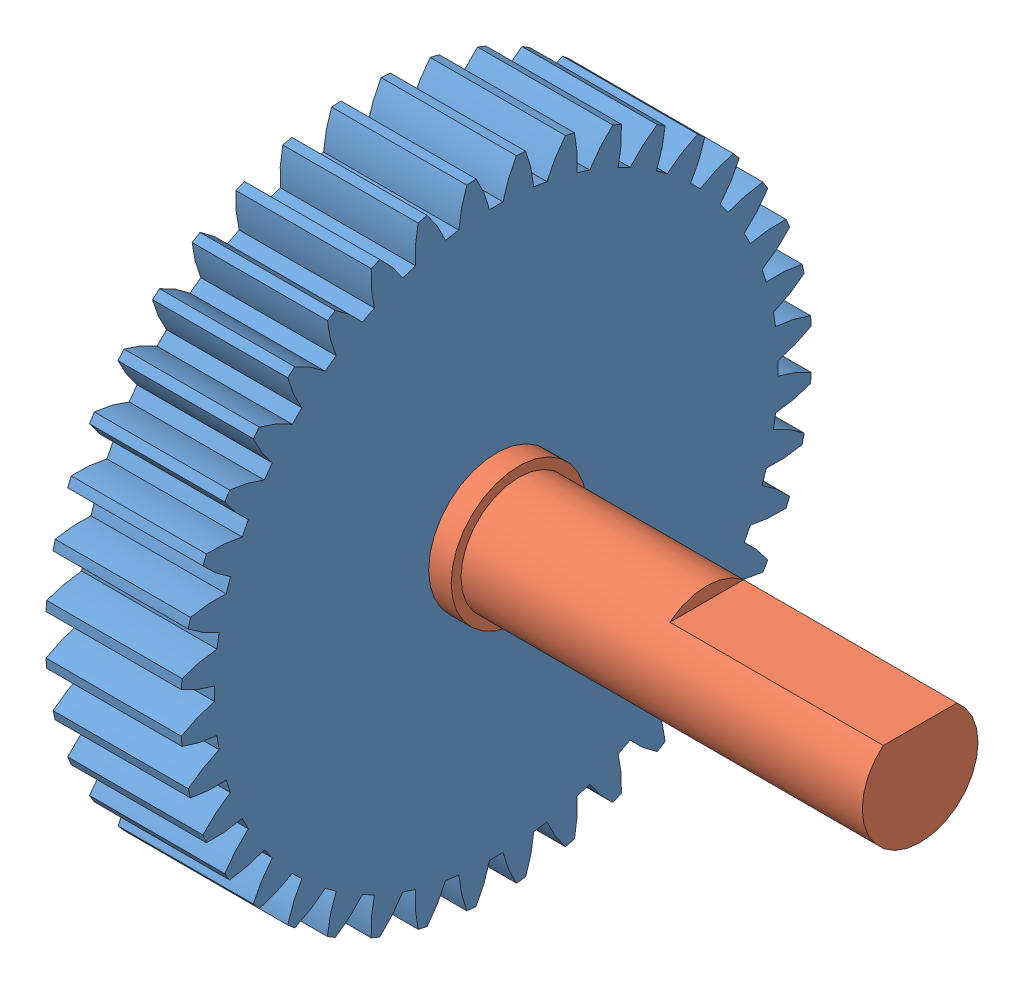
SolidWorks assembly 40_Tooth_Mod1, configuration Default. Lengths in mm.
Overall size (37.2 41.91 41.91).
2 component instances, 2 part files, 2 mates.
Components (placement in the parent):
- Metric - Spur gear 1M 40T 20PA 9FW ---S40N75H50L4N-2: Metric - Spur gear 1M 40T 20PA 9FW ---S40N75H50L4N [Metric - Spur gear 1M 40T 20PA 9FW ---S40N75H50L4N] at (6.894 -1.4709 -4.9997) size (9 41.91 41.91)
- Gear_Shaft-1: Gear_Shaft [Default] at (15.894 -1.4709 -4.9997) size (37.2 9 9)
Mates (geometry in assembly coordinates):
- Concentric1: concentric anti-aligned: cylinder of Metric - Spur gear 1M 40T 20PA 9FW ---S40N75H50L4N-2 through (56.894 -1.4709 -4.9997) axis (-1 0 0) radius 2; cylinder of Gear_Shaft-1 through (6.894 -1.4709 -4.9997) axis (1 0 0) radius 3.85
- Coincident5: coincident aligned: plane of Metric - Spur gear 1M 40T 20PA 9FW ---S40N75H50L4N-2 through (6.894 -1.4709 -4.9997) normal (-1 0 0); plane of Gear_Shaft-1 through (6.894 -1.4709 -4.9997) normal (-1 0 0)
